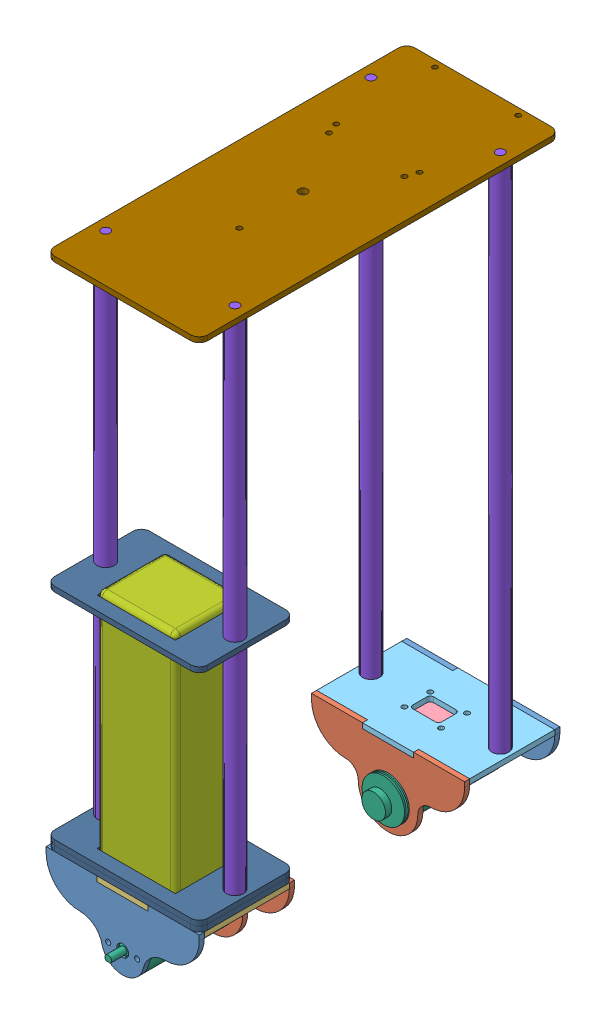
SolidWorks assembly Remake, configuration Default. Lengths in mm.
Overall size (90 351 229).
25 component instances, 17 part files, 54 mates.
Components (placement in the parent):
- motor bracket-1: motor bracket [Default] at (26.3315 37.9818 73.1037) size (90 43 3)
- Rear motor bracket-1: Rear motor bracket [Default] at (26.3315 37.9818 20.1037) size (90 48 3)
- motor bracket-2: motor bracket [Default] at (26.3315 37.9818 -132.8963) x (-1 0 0) z (0 0 -1) size (90 43 3)
- Rear motor bracket-2: Rear motor bracket [Default] at (26.3315 37.9818 -79.8963) x (-1 0 0) z (0 0 -1) size (90 48 3)
- Part1^Remake-1: Part1^Remake [Default] at (26.3315 65.4818 73.1037) x (1 0 0) z (0 1 0) size (90 56 3) (virtual)
- Part2^Remake-1: Part2^Remake [Default] at origin (virtual)
- Orientation sensor-1: Orientation sensor [Default] at (26.3315 62.4818 -107.8963) size (26.67 3 20.32)
- Part3^Remake-1: Part3^Remake [Default] at (26.3315 65.4818 -79.8963) x (-1 0 0) z (0 1 0) size (90 56 3) (virtual)
- Motor-1: Motor [Default] at (26.3315 37.9818 84.6037) x (0 0 -1) z (-1 0 0) size (73 25 25)
- Motor-2: Motor [Default] at (26.3315 37.9818 -144.3963) x (0 0 1) z (-1 0 0) size (73 25 25)
- Battery-1: Battery [Default] at (26.3315 68.4818 48.1037) size (46 138 40)
- Part5^Remake-1: Part5^Remake [Default] at (128.6629 -5.4451 48.1037) size (10 306 10) (virtual)
- Part5^Remake-2: Part5^Remake [Default] at (91.6895 -5.4451 -166.1206) x (0.425267 0 -0.905068) z (0.905068 0 0.425267) size (10 306 10) (virtual)
- Part5^Remake-3: Part5^Remake [Default] at (-74.6943 -5.4451 35.2083) x (-0.979703 0 -0.200453) z (0.200453 0 -0.979703) size (10 306 10) (virtual)
- Part5^Remake-4: Part5^Remake [Default] at (-76 -5.4451 -107.8963) x (-1 0 0) z (0 0 -1) size (10 306 10) (virtual)
- Part6^Remake-1: Part6^Remake [Default] at (128.6629 368.4818 48.1037) x (1 0 0) z (0 1 0) size (90 212 3) (virtual)
- Part7^Remake-1: Part7^Remake [Default] at (26.3315 68.4818 73.1037) x (1 0 0) z (0 1 0) size (90 56 3) (virtual)
- Part7^Remake-2: Part7^Remake [Default] at (26.3315 71.4818 73.1037) x (1 0 0) z (0 1 0) size (90 56 3) (virtual)
- Part7^Remake-3: Part7^Remake [Default] at (26.3315 200.4818 73.1037) x (1 0 0) z (0 1 0) size (90 56 3) (virtual)
- Motor controller PCB-1: Motor controller PCB [Default] at (26.3315 360.4818 -102.8963) size (56.02 3 71.58)
- Part8^Remake-1: Part8^Remake [Default] at origin (virtual)
- Part9^Remake-1: Part9^Remake [Default] at origin (virtual)
- Part10^Remake-1: Part10^Remake [Default] at origin (virtual)
- Part11^Remake-1: Part11^Remake [Default] at origin (virtual)
- Part12^Remake-1: Part12^Remake [Default] at origin (virtual)
Mates (geometry in assembly coordinates):
- Parallel1: parallel aligned: plane of motor bracket-1 through (11.3315 65.4818 76.1037) normal (0 1 0); plane of Rear motor bracket-1 through (11.3315 65.4818 23.1037) normal (0 1 0)
- Concentric1: concentric aligned: cylinder of motor bracket-1 through (26.3315 37.9818 76.1037) axis (0 0 -1) radius 3.5; cylinder of Rear motor bracket-1 through (26.3315 37.9818 23.1037) axis (0 0 -1) radius 12.5
- Distance1: distance = 50 mm anti-aligned: plane of motor bracket-1 through (1.3315 65.4818 73.1037) normal (0 0 -1); plane of Rear motor bracket-1 through (1.3315 65.4818 23.1037) normal (0 0 1)
- Parallel2: parallel aligned: plane of motor bracket-2 through (41.3315 65.4818 -135.8963) normal (0 1 0); plane of Rear motor bracket-2 through (41.3315 65.4818 -82.8963) normal (0 1 0)
- Concentric2: concentric aligned: cylinder of motor bracket-2 through (26.3315 37.9818 -135.8963) axis (0 0 1) radius 3.5; cylinder of Rear motor bracket-2 through (26.3315 37.9818 -82.8963) axis (0 0 1) radius 12.5
- Distance2: distance = 50 mm anti-aligned: plane of motor bracket-2 through (51.3315 65.4818 -132.8963) normal (0 0 1); plane of Rear motor bracket-2 through (51.3315 65.4818 -82.8963) normal (0 0 -1)
- Distance4: distance = 100 mm anti-aligned: plane of Rear motor bracket-1 through (1.3315 65.4818 20.1037) normal (0 0 -1); plane of Rear motor bracket-2 through (51.3315 65.4818 -79.8963) normal (0 0 1)
- Coincident6: coincident aligned: plane of Rear motor bracket-1 through (11.3315 65.4818 23.1037) normal (0 1 0); plane of Rear motor bracket-2 through (41.3315 65.4818 -82.8963) normal (0 1 0)
- Concentric3: concentric anti-aligned: cylinder of Rear motor bracket-1 through (26.3315 37.9818 23.1037) axis (0 0 -1) radius 12.5; cylinder of Rear motor bracket-2 through (26.3315 37.9818 -82.8963) axis (0 0 1) radius 12.5
- InPlace1: in place: plane of motor bracket-1 through (11.3315 65.4818 76.1037) normal (0 1 0); plane of ? through (0 65.4818 0) normal (0 1 0); moOrthogonalPlaneRef_w of motor bracket-1 through (11.3315 65.4818 76.1037) normal (0 1 0); plane of ? through (0 65.4818 0) normal (0 0 -1); plane of motor bracket-1 through (11.3315 65.4818 76.1037) normal (0 1 0); plane of ? through (0 65.4818 0) normal (1 0 0); plane of motor bracket-1 through (11.3315 65.4818 76.1037) normal (0 1 0); unknown of Part1^Remake-1
- Coincident7: coincident aligned: plane of motor bracket-1; plane of Part1^Remake-1
- Coincident8: coincident aligned: moOrthogonalPlaneRef_w of motor bracket-1 through (26.3315 65.4818 73.1037) normal (0 0 -1); plane of Part1^Remake-1 through (26.3315 65.4818 73.1037) normal (0 0 -1)
- Coincident9: coincident anti-aligned: moOrthogonalPlaneRef_w of motor bracket-1 through (26.3315 65.4818 73.1037) normal (-1 0 0); plane of Part1^Remake-1 through (26.3315 65.4818 73.1037) normal (1 0 0)
- InPlace2: in place: plane of ? through (41.3315 65.4818 -52.8963) normal (0 1 0); plane of ? through (0 65.4818 0) normal (0 1 0); plane of ? through (41.3315 65.4818 -52.8963) normal (0 1 0); plane of ? through (0 65.4818 0) normal (0 0 -1); plane of ? through (41.3315 65.4818 -52.8963) normal (0 1 0); plane of ? through (0 65.4818 0) normal (1 0 0); plane of Rear motor bracket-2 through (41.3315 65.4818 -82.8963) normal (0 1 0); unknown of Part3^Remake-1
- Coincident13: coincident aligned: plane of Rear motor bracket-2; plane of Part3^Remake-1
- Coincident14: coincident aligned: moOrthogonalPlaneRef_w of Rear motor bracket-2 through (26.3315 65.4818 -79.8963) normal (0 0 1); plane of Part3^Remake-1 through (26.3315 65.4818 -79.8963) normal (0 0 1)
- Coincident15: coincident anti-aligned: moOrthogonalPlaneRef_w of Rear motor bracket-2 through (26.3315 65.4818 -79.8963) normal (1 0 0); plane of Part3^Remake-1 through (26.3315 65.4818 -79.8963) normal (-1 0 0)
- Coincident16: coincident anti-aligned: plane of Orientation sensor-1 through (26.3315 65.4818 -107.8963) normal (0 1 0); plane of Part3^Remake-1 through (26.3315 65.4818 -79.8963) normal (0 -1 0)
- Concentric4: concentric aligned: cylinder of Orientation sensor-1 through (37.1265 65.4818 -100.2763) axis (0 -1 0) radius 1.45; cylinder of Part3^Remake-1 through (37.1265 68.4818 -100.2763) axis (0 -1 0) radius 1.5
- Concentric5: concentric aligned: cylinder of Orientation sensor-1 through (15.5365 65.4818 -115.5163) axis (0 -1 0) radius 1.45; cylinder of Part3^Remake-1 through (15.5365 68.4818 -115.5163) axis (0 -1 0) radius 1.5
- Concentric6: concentric anti-aligned: cylinder of Rear motor bracket-1 through (26.3315 37.9818 23.1037) axis (0 0 -1) radius 12.5; cylinder of Motor-1 through (26.3315 37.9818 84.6037) axis (0 0 1) radius 12.5
- Concentric7: concentric anti-aligned: cylinder of Rear motor bracket-2 through (26.3315 37.9818 -82.8963) axis (0 0 1) radius 12.5; cylinder of Motor-2 through (26.3315 37.9818 -144.3963) axis (0 0 -1) radius 12.5
- Concentric8: concentric anti-aligned: cylinder of motor bracket-2 through (34.8315 37.9818 -135.8963) axis (0 0 1) radius 1.5; cylinder of Motor-2 through (34.8315 37.9818 -132.8963) axis (0 0 -1) radius 1.25
- Coincident17: coincident anti-aligned: plane of motor bracket-2 through (51.3315 65.4818 -132.8963) normal (0 0 1); plane of Motor-2 through (26.3315 41.4818 -132.8963) normal (0 0 -1)
- Coincident18: coincident anti-aligned: plane of motor bracket-1 through (1.3315 65.4818 73.1037) normal (0 0 -1); plane of Motor-1 through (26.3315 34.4818 73.1037) normal (0 0 1)
- Concentric9: concentric anti-aligned: cylinder of motor bracket-1 through (34.8315 37.9818 76.1037) axis (0 0 -1) radius 1.5; cylinder of Motor-1 through (34.8315 37.9818 73.1037) axis (0 0 1) radius 1.25
- Concentric10: concentric aligned: cylinder of Part1^Remake-1 through (-11.6685 68.4818 48.1037) axis (0 -1 0) radius 2.5; cylinder of Part5^Remake-3 through (-11.6685 65.4818 48.1037) axis (0 -1 0) radius 2.5
- Coincident25: coincident anti-aligned: plane of Part1^Remake-1 through (26.3315 68.4818 73.1037) normal (0 1 0); plane of Part5^Remake-3 through (-16.567 68.4818 47.1015) normal (0 -1 0)
- Concentric11: concentric aligned: cylinder of Part3^Remake-1 through (-11.6685 68.4818 -107.8963) axis (0 -1 0) radius 2.5; cylinder of Part5^Remake-4 through (-11.6685 65.4818 -107.8963) axis (0 -1 0) radius 2.5
- Coincident26: coincident anti-aligned: plane of Part3^Remake-1 through (26.3315 68.4818 -79.8963) normal (0 1 0); plane of Part5^Remake-4 through (-16.6685 68.4818 -107.8963) normal (0 -1 0)
- Concentric12: concentric aligned: cylinder of Part3^Remake-1 through (64.3315 68.4818 -107.8963) axis (0 -1 0) radius 2.5; cylinder of Part5^Remake-2 through (64.3315 65.4818 -107.8963) axis (0 -1 0) radius 2.5
- Coincident27: coincident anti-aligned: plane of Part3^Remake-1 through (26.3315 68.4818 -79.8963) normal (0 1 0); plane of Part5^Remake-2 through (66.4578 68.4818 -112.4216) normal (0 -1 0)
- InPlace5: in place: plane of ? through (63.8315 368.4818 48.1037) normal (0 1 0); plane of ? through (0 368.4818 0) normal (0 1 0); plane of ? through (63.8315 368.4818 48.1037) normal (0 1 0); plane of ? through (0 368.4818 0) normal (0 0 -1); plane of ? through (63.8315 368.4818 48.1037) normal (0 1 0); plane of ? through (0 368.4818 0) normal (1 0 0); plane of Part5^Remake-1 through (66.8315 368.4818 48.1037) normal (0 1 0); unknown of Part6^Remake-1
- Coincident28: coincident aligned: plane of Part5^Remake-1; plane of Part6^Remake-1
- Coincident29: coincident aligned: moOrthogonalPlaneRef_w of Part5^Remake-1 through (128.6629 368.4818 48.1037) axis (0 0 -1); plane of Part6^Remake-1 through (128.6629 368.4818 48.1037) normal (0 0 -1)
- Coincident30: coincident anti-aligned: moOrthogonalPlaneRef_w of Part5^Remake-1; plane of Part6^Remake-1 through (128.6629 368.4818 48.1037) normal (1 0 0)
- InPlace6: in place: plane of Part1^Remake-1 through (26.3315 68.4818 73.1037) normal (0 1 0); plane of ? through (0 68.4818 0) normal (0 1 0); plane of Part1^Remake-1 through (26.3315 68.4818 73.1037) normal (0 1 0); plane of ? through (0 68.4818 0) normal (0 0 -1); plane of Part1^Remake-1 through (26.3315 68.4818 73.1037) normal (0 1 0); plane of ? through (0 68.4818 0) normal (1 0 0); plane of Part1^Remake-1 through (26.3315 68.4818 73.1037) normal (0 1 0); unknown of Part7^Remake-1
- Coincident32: coincident aligned: plane of Part1^Remake-1; plane of Part7^Remake-1
- Coincident33: coincident aligned: moOrthogonalPlaneRef_w of Part1^Remake-1 through (26.3315 68.4818 73.1037) normal (0 0 -1); plane of Part7^Remake-1 through (26.3315 68.4818 73.1037) normal (0 0 -1)
- Coincident34: coincident anti-aligned: moOrthogonalPlaneRef_w of Part1^Remake-1 through (26.3315 68.4818 73.1037) normal (-1 0 0); plane of Part7^Remake-1 through (26.3315 68.4818 73.1037) normal (1 0 0)
- Coincident35: coincident anti-aligned: plane of Battery-1 through (3.3315 206.4818 28.1037) normal (0 0 -1); plane of Part7^Remake-1 through (49.3315 71.4818 28.1037) normal (0 0 1)
- Coincident36: coincident anti-aligned: plane of Battery-1 through (49.3315 206.4818 68.1037) normal (1 0 0); plane of Part7^Remake-1 through (49.3315 71.4818 68.1037) normal (-1 0 0)
- Coincident37: coincident anti-aligned: plane of Part1^Remake-1 through (26.3315 68.4818 73.1037) normal (0 1 0); plane of Battery-1 through (26.3315 68.4818 48.1037) normal (0 -1 0)
- Concentric13: concentric aligned: cylinder of Part5^Remake-1 through (64.3315 65.4818 48.1037) axis (0 -1 0) radius 5; cylinder of Part7^Remake-2 through (64.3315 74.4818 48.1037) axis (0 -1 0) radius 5
- Concentric15: concentric aligned: cylinder of Part5^Remake-3 through (-11.6685 65.4818 48.1037) axis (0 -1 0) radius 5; cylinder of Part7^Remake-2 through (-11.6685 74.4818 48.1037) axis (0 -1 0) radius 5
- Coincident38: coincident anti-aligned: plane of Part7^Remake-1 through (26.3315 71.4818 73.1037) normal (0 1 0); plane of Part7^Remake-2 through (26.3315 71.4818 73.1037) normal (0 -1 0)
- Coincident39: coincident: line of Battery-1 through (49.3315 203.4818 31.1037) axis (0 0 1); plane of Part7^Remake-3 through (26.3315 203.4818 73.1037) normal (0 1 0)
- Concentric16: concentric aligned: cylinder of Part5^Remake-1 through (64.3315 65.4818 48.1037) axis (0 -1 0) radius 5; cylinder of Part7^Remake-3 through (64.3315 203.4818 48.1037) axis (0 -1 0) radius 5
- Concentric17: concentric aligned: cylinder of Part5^Remake-3 through (-11.6685 65.4818 48.1037) axis (0 -1 0) radius 5; cylinder of Part7^Remake-3 through (-11.6685 203.4818 48.1037) axis (0 -1 0) radius 5
- Distance5: distance = 5 mm anti-aligned: plane of Motor controller PCB-1 through (26.3315 363.4818 -102.8963) normal (0 1 0); plane of Part6^Remake-1 through (128.6629 368.4818 48.1037) normal (0 -1 0)
- Concentric24: concentric aligned: cylinder of Part1^Remake-1 through (64.3315 68.4818 48.1037) axis (0 -1 0) radius 2.5; cylinder of Part5^Remake-1 through (64.3315 65.4818 48.1037) axis (0 -1 0) radius 2.5
- Coincident48: coincident anti-aligned: plane of Part1^Remake-1 through (26.3315 68.4818 73.1037) normal (0 1 0); plane of Part5^Remake-1 through (69.3315 68.4818 48.1037) normal (0 -1 0)
- Concentric31: concentric aligned: cylinder of Part6^Remake-1 through (50.8315 371.4818 -131.8963) axis (0 -1 0) radius 1.45; cylinder of Motor controller PCB-1 through (50.8315 363.4818 -131.8963) axis (0 -1 0) radius 1.45
- Concentric32: concentric aligned: cylinder of Part6^Remake-1 through (50.8315 371.4818 -73.8963) axis (0 -1 0) radius 1.45; cylinder of Motor controller PCB-1 through (50.8315 363.4818 -73.8963) axis (0 -1 0) radius 1.45
